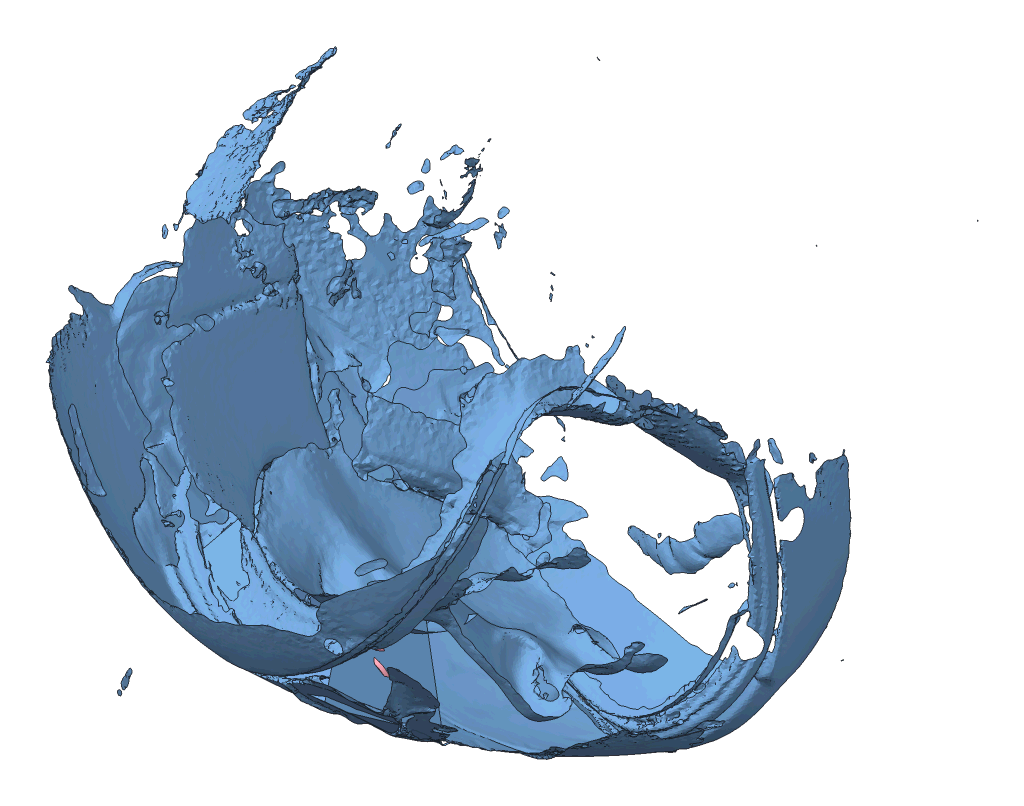
SolidWorks assembly asm, configuration По умолчанию. Lengths in mm.
Overall size (270.91 239.79 235.47).
5 component instances, 4 part files, 2 mates.
Components (placement in the parent):
- helmet with face v3-1: helmet with face v3 [По умолчанию] at origin size (270.91 239.79 235.47)
- okular-1: okular [По умолчанию] at (-500.6053 890.0701 4091.668) x (0.961022 0.266183 0.074727) z (0.012036 0.22975 -0.973175) size (39 20 18.3)
  - lensHolder-1: lensHolder [По умолчанию] at origin size (29.5 16.75 9.4)
  - display-1: display [По умолчанию] at (0.075 0.225 -5.75) size (14.55 16.9 4)
  - cover-1: cover [По умолчанию] at (-0.2 -0.075 7.35) x (1 0 0) z (0 0 -1) size (39 20 7.2)
Mates (geometry in assembly coordinates):
- Расстояние1: distance = 25 mm: point of okular-1/cover-1; point of helmet with face v3-1
- Совпадение3: coincident: unknown of okular-1/cover-1
